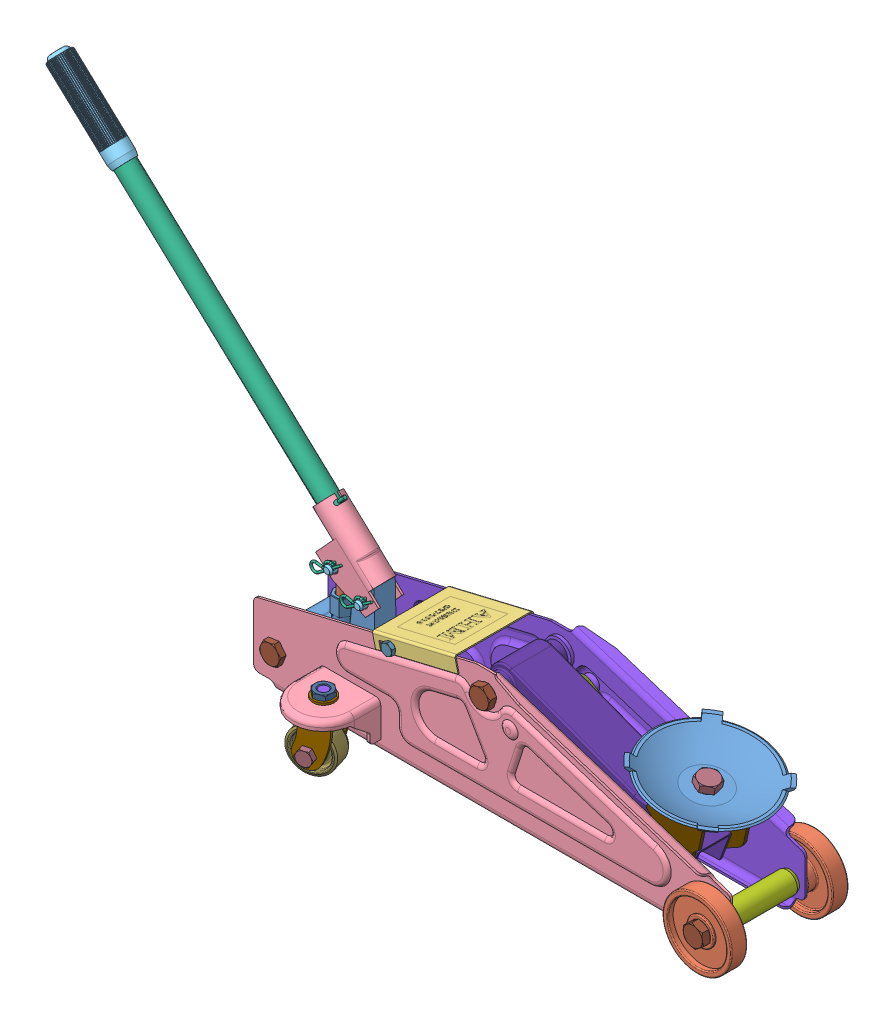
SolidWorks assembly HYDRAULIC FLOOR JACK, configuration Default. Lengths in mm.
Overall size (721.63 435.05 180).
66 component instances, 32 part files, 97 mates.
Components (placement in the parent):
- Part3-1: Part3 [Default] at (-30.7327 -45.0544 -105.304) x (0.999747 0.022492 0) z (0 0 1) size (169.5 91.5 56)
- Part16-1: Part16 [Default] at (-47.0325 12.5554 -112.804) x (-0.022492 0.999747 0) z (-0.262072 -0.005896 0.96503) size (45 10.25 10.25)
- Part14-1: Part14 [Default] at (-47.1112 16.0545 -112.804) x (0 0 1) z (-0.999747 -0.022492 0) size (14 17 19)
- Part6-1: Part6 [Default] at (-25.1366 29.0482 -113.304) x (0.733776 -0.679391 0) z (0 0 1) size (81 40.24 24)
- clevis pin headed_iso-1: clevis pin headed_iso [ISO 2341 - B - 8 x 30 x 2 - St] at (-43.8608 19.1284 -128.304) x (0 0 1) z (-0.796609 -0.604495 0) size (33 14 14)
- clevis pin headed_iso-2: clevis pin headed_iso [ISO 2341 - B - 8 x 30 x 2 - St] at (-15.3389 4.3044 -128.304) x (0 0 1) z (-0.830497 -0.557024 0) size (33 14 14)
- Part17-1: Part17 [Default] at (-4.0659 11.8653 -98.804) x (0.830497 0.557024 0) z (0 0 1) size (33.1 10.2 2)
- Part17-2: Part17 [Default] at (-33.0478 27.3337 -98.804) x (0.796609 0.604495 0) z (0 0 1) size (33.1 10.2 2)
- spring pin slotted_hd_iso2-2: spring pin slotted_hd_iso2 [ISO 8752 - 14 x 65 - St] at (-67.7233 -45.8866 -137.804) x (0 0 1) z (0.610683 -0.791875 0) size (65 14 13.98)
- Part1-1: Part1 [Default] at (361.7767 -71.5391 -140.804) x (-1 0 0) z (0 0 -1) size (450 122.47 64)
- Part15-1: Part15 [Default] at (2.7767 -45.1322 -167.804) x (0.289152 0 -0.957283) z (0.957283 0 0.289152) size (38 61.13 38)
- Part18-1: Part18 [Default] at (-8.112 -40.5391 -173.9429) x (0.278126 -0.941875 0.188462) z (-0.474023 -0.305233 -0.825914) size (6 6 6)
- Part19-1: Part19 [Default] at (2.7767 -40.5391 -167.804) x (-0.010236 0 -0.999948) z (-0.999948 0 0.010236) size (38 2 38)
- Part18-2: Part18 [Default] at (2.6488 -40.5391 -180.3034) x (-0.02415 -0.941875 0.335095) z (0.478251 -0.305233 -0.823473) size (6 6 6)
- Part18-3: Part18 [Default] at (13.5375 -40.5391 -174.1645) x (-0.302276 -0.941875 0.146633) z (0.952275 -0.305233 0.002441) size (6 6 6)
- Part18-4: Part18 [Default] at (13.6654 -40.5391 -161.6652) x (-0.278126 -0.941875 -0.188462) z (0.474023 -0.305233 0.825914) size (6 6 6)
- Part18-5: Part18 [Default] at (2.9046 -40.5391 -155.3047) x (0.02415 -0.941875 -0.335095) z (-0.478251 -0.305233 0.823473) size (6 6 6)
- Part18-6: Part18 [Default] at (-7.9841 -40.5391 -161.4436) x (0.302276 -0.941875 -0.146633) z (-0.952275 -0.305233 -0.002441) size (6 6 6)
- Part10-1: Part10 [Default] at (-2.0097 -76.1322 -169.2498) x (0.846792 0.466391 0.255778) z (0.446468 -0.884579 0.134858) size (40.08 21 40.08)
- hex bolt gradeb_iso-1: hex bolt gradeb_iso [ISO 4015 - M8 x 35 x 22-S] at (3.5709 -76.1322 -187.7254) x (-0.289152 0 0.957283) z (0.028855 0.999546 0.008716) size (40.3 15.01 13)
- hex thin nut gradeb_iso-2: hex thin nut gradeb_iso [ISO - 4036 - M8 - S] at (-7.2145 -76.1322 -152.0187) x (0.374692 -0.920216 0.113178) z (-0.289152 0 0.957283) size (13 15.01 4)
- Part4-1: Part4 [Default] at (-2.2334 -44.4132 -105.304) x (0.999747 0.022492 0) z (-0.022492 0.999747 0) size (133 25 25)
- Part20-1: Part20 [Default] at (210.0163 -29.2774 -137.804) x (0.851833 -0.523814 0) z (0 0 1) size (145 20 3)
- Part5-1: Part5 [Default] at (122.9941 38.2707 -107.804) x (0 0 1) z (0.936412 -0.350903 0) size (58 99.23 200.26)
- Part7-1: Part7 [Default] at (307.743 31.1726 -82.3383) x (0.208686 0.977983 0) z (-0.977983 0.208686 0) size (87.89 54.93 59.06)
- Part9-1: Part9 [Default] at (303.0404 9.1345 -106.804) x (0.702008 -0.149797 -0.696237) z (0.680907 -0.145295 0.717812) size (116.71 17 116.71)
- Part11-1: Part11 [Default] at (349.2767 -59.0438 -143.054) x (-0.815982 0.578077 0) z (-0.578077 -0.815982 0) size (65 19 65)
- spring pin slotted_hd_iso2-3: spring pin slotted_hd_iso2 [ISO 8752 - 18 x 12 - St] at (349.2767 -59.0438 -144.054) x (0 0 -1) z (-0.9622 -0.272344 0) size (12 18 17.97)
- Part8-1: Part8 [Default] at (63.7575 25.6748 -106.804) x (0 0 1) z (0.972806 0.231621 0) size (74 14 80)
- Part2-1: Part2 [Default] at (361.7767 -71.5391 -72.804) x (-1 0 0) z (0 0 -1) size (450 122.47 64)
- Part15-2: Part15 [Default] at (2.7767 -45.1322 -45.804) x (-0.289152 0 -0.957283) z (0.957283 0 -0.289152) size (38 61.13 38)
- Part18-7: Part18 [Default] at (-8.112 -40.5391 -39.6652) x (0.278126 -0.941875 -0.188462) z (0.474023 0.305233 -0.825914) size (6 6 6)
- Part19-2: Part19 [Default] at (2.7767 -40.5391 -45.804) x (0.010236 0 -0.999948) z (-0.999948 0 -0.010236) size (38 2 38)
- Part10-2: Part10 [Default] at (-2.0097 -76.1322 -44.3583) x (0.846792 0.466391 -0.255778) z (-0.446468 0.884579 0.134858) size (40.08 21 40.08)
- hex bolt gradeb_iso-2: hex bolt gradeb_iso [ISO 4015 - M8 x 35 x 22-S] at (3.5709 -76.1322 -25.8827) x (-0.289152 0 -0.957283) z (-0.028855 -0.999546 0.008716) size (40.3 15.01 13)
- hex thin nut gradeb_iso-3: hex thin nut gradeb_iso [ISO - 4036 - M8 - S] at (-6.0578 -76.1322 -57.7602) x (0.374692 -0.920216 -0.113178) z (0.289152 0 0.957283) size (13 15.01 4)
- Part20-2: Part20 [Default] at (210.0163 -29.2774 -78.804) x (0.851833 -0.523814 0) z (0 0 1) size (145 20 3)
- spring pin slotted_hd_iso2-4: spring pin slotted_hd_iso2 [ISO 8752 - 18 x 12 - St] at (349.2767 -59.0438 -57.554) x (0 0 -1) z (-0.9622 -0.272344 0) size (12 18 17.97)
- Part11-2: Part11 [Default] at (349.2767 -59.0438 -70.554) x (-0.815982 0.578077 0) z (0.578077 0.815982 0) size (65 19 65)
- Part12-1: Part12 [Default] at (-251.8735 238.98 -113.304) x (-0.423177 -0.457052 0.78232) z (-0.531501 -0.574048 -0.622877) size (22.2 88 22.2)
- Part21-1: Part21 [Default] at (-33.9419 37.2009 -113.304) x (0.679391 0.733776 0) z (0 0 1) size (26 380 18)
- spring pin slotted_hd_iso-1: spring pin slotted_hd_iso [ISO 8752 - 14 x 65 - St] at (131.7767 18.9609 -139.304) x (0 0 1) z (-0.237226 0.971454 0) size (65 14 13.98)
- hexalobular socket cheese head_iso-1: hexalobular socket cheese head_iso [ISO 14580 - #10 x 16 x 13 - 4.8-S] at (2.7767 -29.1322 -45.804) x (-0.068609 0 -0.997644) z (-0.997644 0 0.068609) size (16 22.9 16)
- plain washer 10673 type snl_iso-1: plain washer 10673 type snl_iso [ISO 10673-11-S] at (2.7767 -33.5391 -45.804) x (0 -1 0) z (-0.63842 0 0.769688) size (2 20 20)
- hex thin nut chamfered gradeab_iso-1: hex thin nut chamfered gradeab_iso [ISO - 4035 - M10 - S] at (2.7767 -28.5391 -45.804) x (0.990758 0 0.135644) z (0 1 0) size (16 18.48 5)
- hex bolt gradeab_iso-1: hex bolt gradeab_iso [ISO 4014 - M12 x 80 x 30-S] at (-67.7233 -45.8866 -65.304) x (0 0 -1) z (-0.143117 0.989706 0) size (87.5 20.78 18)
- hex bolt gradeab_iso-2: hex bolt gradeab_iso [ISO 4014 - M12 x 80 x 30-S] at (131.7767 18.9609 -63.304) x (0 0 -1) z (-0.965945 0.258746 0) size (87.5 20.78 18)
- hex bolt gradeab_iso-3: hex bolt gradeab_iso [ISO 4014 - M12 x 110 x 30-S] at (349.2767 -59.0438 -47.654) x (0 0 -1) z (0.609692 -0.792638 0) size (117.5 20.78 18)
- spring pin slotted_hd_iso-2: spring pin slotted_hd_iso [ISO 8752 - 20 x 65 - St] at (349.2767 -59.0438 -139.304) x (0 0 1) z (-0.928845 -0.370468 0) size (65 20 19.97)
- plain washer clevis pin grade a_iso-1: plain washer clevis pin grade a_iso [ISO 8738 - 12] at (349.2767 -59.0438 -159.054) x (0 0 1) z (-1 0 0) size (3 20 20)
- plain washer clevis pin grade a_iso-2: plain washer clevis pin grade a_iso [ISO 8738 - 12] at (131.7767 18.9609 -142.804) x (0 0 1) z (-1 0 0) size (3 20 20)
- plain washer clevis pin grade a_iso-3: plain washer clevis pin grade a_iso [ISO 8738 - 12] at (-67.7233 -45.8866 -142.804) x (0 0 1) z (-1 0 0) size (3 20 20)
- hex thin nut chamfered gradeab_iso-2: hex thin nut chamfered gradeab_iso [ISO - 4035 - M12 - N] at (349.2767 -59.0438 -168.054) x (0.808569 0.588401 0) z (0 0 -1) size (18 20.78 6)
- hex thin nut chamfered gradeab_iso-3: hex thin nut chamfered gradeab_iso [ISO - 4035 - M12 - N] at (131.7767 18.9609 -151.804) x (0.923728 0.383049 0) z (0 0 -1) size (18 20.78 6)
- hex thin nut chamfered gradeab_iso-4: hex thin nut chamfered gradeab_iso [ISO - 4035 - M12 - N] at (-67.7233 -45.8866 -151.804) x (0.923728 0.383049 0) z (0 0 -1) size (18 20.78 6)
- hexalobular socket cheese head_iso-2: hexalobular socket cheese head_iso [ISO 14580 - #10 x 16 x 13 - 4.8-S] at (2.7767 -29.1322 -167.804) x (-0.068609 0 0.997644) z (0.997644 0 0.068609) size (16 22.9 16)
- plain washer 10673 type snl_iso-2: plain washer 10673 type snl_iso [ISO 10673-11-S] at (2.7767 -33.5391 -167.804) x (0 -1 0) z (0.63842 0 0.769688) size (2 20 20)
- hex thin nut chamfered gradeab_iso-5: hex thin nut chamfered gradeab_iso [ISO - 4035 - M10 - S] at (2.7767 -33.5391 -167.804) x (0.990758 0 -0.135644) z (0 -1 0) size (16 18.48 5)
- clevis pin headed_iso-3: clevis pin headed_iso [ISO 2341 - B - 16 x 50 x 4 - St] at (119.7357 -41.6692 -132.304) x (0 0 1) z (-0.487474 0.873138 0) size (54.5 25 25)
- clevis pin headed_iso-5: clevis pin headed_iso [ISO 2341 - B - 12 x 60 x 3.2 - St] at (292.1959 -41.6871 -75.3383) x (0 0 -1) z (0.694321 -0.719666 0) size (64 20 20)
- hex screw gradeab fine_iso-1: hex screw gradeab fine_iso [ISO 8676 - M12x1.5 x 25-S] at (305.2316 19.4033 -106.804) x (-0.208686 -0.977983 0) z (-0.641055 0.136791 -0.755207) size (32.5 20.78 18)
- hex thin nut chamfered gradeab_iso-6: hex thin nut chamfered gradeab_iso [ISO - 4035 - M12 - S] at (289.2862 2.8668 -107.0926) x (0.965138 -0.205945 0.161538) z (-0.208686 -0.977983 0) size (18 20.78 6)
- hex screw gradeab_iso-1: hex screw gradeab_iso [ISO 4017 - M6 x 12-S] at (41.7767 12.2176 -147.804) x (0 0 1) z (-0.99469 0.102914 0) size (16 11.55 10)
- hex thin nut chamfered gradeab_iso-7: hex thin nut chamfered gradeab_iso [ISO - 4035 - M6 - S] at (41.7767 12.2176 -137.604) x (0.611351 0.79136 0) z (0 0 1) size (10 11.55 3.2)
- hex screw gradeab_iso-2: hex screw gradeab_iso [ISO 4017 - M6 x 12-S] at (41.7767 12.2176 -65.804) x (0 0 -1) z (0.99469 -0.102914 0) size (16 11.55 10)
- hex thin nut chamfered gradeab_iso-8: hex thin nut chamfered gradeab_iso [ISO - 4035 - M6 - S] at (41.7767 12.2176 -72.804) x (0.611351 0.79136 0) z (0 0 1) size (10 11.55 3.2)
Mates (geometry in assembly coordinates):
- Concentric3: concentric aligned: cylinder of Part3-1 through (-45.6614 -48.391 -112.804) axis (-0.022492 0.999747 0) radius 5; cylinder of Part16-1 through (-47.0325 12.5554 -112.804) axis (-0.022492 0.999747 0) radius 4.25
- Concentric4: concentric anti-aligned: cylinder of Part16-1 through (-47.0325 12.5554 -112.804) axis (-0.022492 0.999747 0) radius 3.25; cylinder of Part14-1 through (-47.3024 24.5533 -112.804) axis (0.022492 -0.999747 0) radius 3.375
- Width1: width anti-aligned: plane of Part14-1 through (-54.4519 8.8876 -105.804) normal (-0.022492 0.999747 0); plane of Part16-1 through (-54.4182 7.388 -105.804) normal (0.022492 -0.999747 0); plane of Part14-1 through (-46.9538 9.0563 -112.804) normal (0.022492 -0.999747 0); plane of Part16-1 through (-46.9201 7.5566 -112.804) normal (-0.022492 0.999747 0)
- Concentric5: concentric anti-aligned: cylinder of Part6-1 through (-15.3389 4.3044 -101.304) axis (0 0 -1) radius 4.5; cylinder of Part3-1 through (-15.3389 4.3044 -133.304) axis (0 0 1) radius 4.25
- Width2: width anti-aligned: plane of Part3-1 through (-30.7327 -45.0544 -123.304) normal (0 0 -1); plane of Part6-1 through (-30.7327 -45.0544 -103.304) normal (0 0 1); plane of Part3-1 through (-25.1366 29.0482 -123.304) normal (0 0 1); plane of Part6-1 through (-25.1366 29.0482 -103.304) normal (0 0 -1)
- Parallel1: parallel aligned: plane of Part14-1 through (-41.7138 20.6771 -119.804) normal (0 0 -1); plane of Part6-1 through (-25.1366 29.0482 -125.304) normal (0 0 -1)
- Concentric6: concentric anti-aligned: cylinder of Part6-1 through (-43.8608 19.1284 -125.304) axis (0 0 1) radius 5; cylinder of clevis pin headed_iso-1 through (-43.8608 19.1284 -128.304) axis (0 0 -1) radius 7
- Coincident1: coincident anti-aligned: plane of Part6-1 through (-25.1366 29.0482 -125.304) normal (0 0 -1); plane of clevis pin headed_iso-1 through (-48.0923 24.7046 -125.304) normal (0 0 1)
- Concentric7: concentric anti-aligned: cylinder of Part6-1 through (-15.3389 4.3044 -125.304) axis (0 0 1) radius 4.5; cylinder of clevis pin headed_iso-2 through (-15.3389 4.3044 -128.304) axis (0 0 -1) radius 7
- Coincident2: coincident anti-aligned: plane of Part6-1 through (-25.1366 29.0482 -125.304) normal (0 0 -1); plane of clevis pin headed_iso-2 through (-19.2381 10.1178 -125.304) normal (0 0 1)
- Tangent2: tangent anti-aligned: plane of Part14-1 through (-52.7673 22.929 -105.804) normal (0.022492 -0.999747 0); cylinder of clevis pin headed_iso-1 through (-43.8608 19.1284 -128.304) axis (0 0 -1) radius 4
- LimitDistance1: limit distance = 15.9618 mm anti-aligned: plane of Part14-1 through (-54.4182 7.388 -105.804) normal (0.022492 -0.999747 0); plane of Part3-1 through (-31.5649 -8.0637 -105.304) normal (-0.022492 0.999747 0)
- Concentric8: concentric aligned: cylinder of clevis pin headed_iso-1 through (-40.6744 21.5464 -98.804) axis (-0.796609 -0.604495 0) radius 1; cylinder of Part17-2 through (-33.0478 27.3337 -98.804) axis (-0.796609 -0.604495 0) radius 1
- Concentric9: concentric aligned: cylinder of clevis pin headed_iso-2 through (-12.0169 6.5325 -98.804) axis (-0.830497 -0.557024 0) radius 1; cylinder of Part17-1 through (-4.0659 11.8653 -98.804) axis (-0.830497 -0.557024 0) radius 1
- Tangent3: tangent anti-aligned: cylinder of clevis pin headed_iso-1 through (-43.8608 19.1284 -128.304) axis (0 0 -1) radius 4; cylinder of Part17-2 through (-48.9777 18.617 -98.804) axis (0.135845 0.99073 0) radius 1
- Parallel2: parallel aligned: plane of Part6-1 through (-25.1366 29.0482 -101.304) normal (0 0 1); plane of Part17-2 through (-33.0478 27.3337 -98.804) normal (0 0 1)
- Parallel4: parallel aligned: plane of Part6-1 through (-25.1366 29.0482 -101.304) normal (0 0 1); plane of Part17-1 through (-4.0659 11.8653 -98.804) normal (0 0 1)
- Tangent5: tangent anti-aligned: cylinder of clevis pin headed_iso-2 through (-15.3389 4.3044 -128.304) axis (0 0 -1) radius 4; cylinder of Part17-1 through (-20.4769 4.0922 -98.804) axis (0.193374 0.981125 0) radius 1
- Concentric12: concentric aligned: cylinder of Part3-1 through (-67.7233 -45.8866 -133.304) axis (0 0 1) radius 7.5; cone of spring pin slotted_hd_iso-2 through (-67.7233 -45.8866 -72.804) axis (0 0 1)
- Width3: width anti-aligned: plane of spring pin slotted_hd_iso-2 through (-72.6725 -49.7033 -137.804) normal (0 0 -1); plane of Part3-1 through (-70.8908 -48.3293 -72.804) normal (0 0 1); plane of spring pin slotted_hd_iso-2 through (-67.7233 -45.8866 -77.304) normal (0 0 1); plane of Part3-1 through (-67.7233 -45.8866 -133.304) normal (0 0 -1)
- Concentric13: concentric aligned: cylinder of spring pin slotted_hd_iso-2 through (-67.7233 -45.8866 -147.329) axis (0 0 -1) radius 4; cylinder of Part1-1 through (-67.7233 -45.8866 -137.804) axis (0 0 -1) radius 7.5
- Coincident8: coincident anti-aligned: plane of spring pin slotted_hd_iso-2 through (-72.6725 -49.7033 -137.804) normal (0 0 -1); plane of Part1-1 through (-67.7233 -45.8866 -137.804) normal (0 0 1)
- Concentric14: concentric: sphere of Part18-1; sphere of Part19-1
- Concentric15: concentric aligned: circle of Part1-1; circle of Part19-1
- Concentric16: concentric anti-aligned: cylinder of Part1-1 through (2.7767 42.9337 -167.804) axis (0 -1 0) radius 6.5; cylinder of Part15-1 through (2.7767 -26.9992 -167.804) axis (0 1 0) radius 7
- Tangent17: tangent anti-aligned: torus of Part1-1; sphere of Part18-3
- Concentric17: concentric anti-aligned: cylinder of Part15-1 through (-6.0578 -76.1322 -155.8478) axis (0.289152 0 -0.957283) radius 5; cylinder of Part10-1 through (-5.9086 -76.1322 -156.3419) axis (-0.289152 0 0.957283) radius 5
- Width4: width anti-aligned: plane of Part10-1 through (-3.2076 -78.4641 -180.5802) normal (0.289152 0 -0.957283); plane of Part15-1 through (-9.2798 -78.4641 -160.4772) normal (-0.289152 0 0.957283); plane of Part10-1 through (17.7399 -59.5549 -174.7752) normal (-0.289152 0 0.957283); plane of Part15-1 through (11.3786 -59.5549 -153.7149) normal (0.289152 0 -0.957283)
- Concentric18: concentric anti-aligned: cylinder of Part15-1 through (2.0384 -76.1322 -182.6518) axis (-0.289152 0 0.957283) radius 5; cylinder of hex bolt gradeb_iso-1 through (3.5709 -76.1322 -187.7254) axis (0.289152 0 -0.957283) radius 4
- Coincident10: coincident anti-aligned: plane of Part15-1 through (18.6074 -59.5549 -177.647) normal (0.289152 0 -0.957283); plane of hex bolt gradeb_iso-1 through (9.2201 -76.3584 -180.4825) normal (-0.289152 0 0.957283)
- Concentric19: concentric anti-aligned: cylinder of Part15-1 through (-6.0578 -76.1322 -155.8478) axis (0.289152 0 -0.957283) radius 12; cylinder of hex thin nut gradeb_iso-2 through (0.0252 -76.1322 -175.9867) axis (-0.289152 0 0.957283) radius 4
- Coincident11: coincident anti-aligned: plane of Part15-1 through (10.5111 -59.5549 -150.8431) normal (-0.289152 0 0.957283); plane of hex thin nut gradeb_iso-2 through (0.5538 -73.1944 -153.8507) normal (0.289152 0 -0.957283)
- Concentric21: concentric aligned: cylinder of Part3-1 through (-81.2209 -46.1902 -105.304) axis (0.999747 0.022492 0) radius 7.5; cylinder of Part4-1 through (130.733 -41.4218 -105.304) axis (0.999747 0.022492 0) radius 7.5
- Concentric22: concentric aligned: cylinder of Part1-1 through (156.7767 3.4609 -133.804) axis (0 0 -1) radius 4.5; cylinder of Part20-1 through (156.7767 3.4609 -134.804) axis (0 0 -1) radius 5.75
- Coincident13: coincident anti-aligned: plane of Part1-1 through (131.7767 18.9609 -137.804) normal (0 0 1); plane of Part20-1 through (156.7767 3.4609 -137.804) normal (0 0 -1)
- Concentric26: concentric aligned: cylinder of Part1-1 through (131.7767 18.9609 -137.804) axis (0 0 -1) radius 7.5; cylinder of Part5-1 through (131.7767 18.9609 -78.804) axis (0 0 -1) radius 10.5
- Distance3: distance = 1 mm anti-aligned: plane of Part1-1 through (131.7767 18.9609 -137.804) normal (0 0 1); plane of Part5-1 through (131.7767 18.9609 -136.804) normal (0 0 -1)
- Concentric28: concentric anti-aligned: cylinder of Part4-1 through (119.7357 -41.6692 -92.804) axis (0 0 -1) radius 8; cylinder of Part5-1 through (119.7357 -41.6692 -127.814) axis (0 0 1) radius 8
- Parallel11: parallel anti-aligned: plane of Part1-1 through (351.7767 -79.5391 -135.804) normal (0 -1 0)
- Concentric29: concentric anti-aligned: cylinder of Part5-1 through (292.1959 -41.6871 -127.814) axis (0 0 1) radius 6.5; cylinder of Part7-1 through (292.1959 -41.6871 -79.3383) axis (0 0 -1) radius 6.25
- Concentric30: concentric anti-aligned: cylinder of Part20-1 through (263.2558 -62.0157 -134.804) axis (0 0 -1) radius 5.75; cylinder of Part7-1 through (263.2558 -62.0157 -134.2697) axis (0 0 1) radius 5.5
- Tangent18: tangent anti-aligned: torus of Part15-1; sphere of Part18-4
- Linear/Linear Coupler3: linear coupler = 1 : 4 mm: cylinder of Part16-1 through (-47.0325 12.5554 -112.804) axis (-0.022492 0.999747 0) radius 4.25; cylinder of Part4-1 through (130.733 -41.4218 -105.304) axis (0.999747 0.022492 0) radius 7.5
- Concentric32: concentric aligned: cylinder of Part7-1 through (284.6998 -76.8167 -106.804) axis (0.208686 0.977983 0) radius 6.5; cylinder of Part9-1 through (303.0404 9.1345 -106.804) axis (0.208686 0.977983 0) radius 6.5
- Coincident18: coincident anti-aligned: plane of Part7-1 through (279.5095 14.1556 -6.3836) normal (0.208686 0.977983 0); plane of Part9-1 through (303.0404 9.1345 -106.804) normal (-0.208686 -0.977983 0)
- Concentric33: concentric aligned: cylinder of Part1-1 through (349.2767 -59.0438 -132.804) axis (0 0 -1) radius 5.5; cylinder of Part11-1 through (349.2767 -59.0438 -171.148) axis (0 0 -1) radius 9
- Distance4: distance = 0.25 mm anti-aligned: plane of Part1-1 through (361.7767 -71.5391 -142.804) normal (0 0 -1); plane of Part11-1 through (359.8845 -66.5588 -143.054) normal (0 0 1)
- Concentric34: concentric aligned: cylinder of Part11-1 through (349.2767 -59.0438 -171.148) axis (0 0 -1) radius 9; cone of spring pin slotted_hd_iso-3 through (349.2767 -59.0438 -156.054) axis (0 0 -1)
- Concentric36: concentric anti-aligned: cylinder of Part5-1 through (131.7767 18.9609 -78.804) axis (0 0 -1) radius 8; cylinder of Part2-1 through (131.7767 18.9609 -80.804) axis (0 0 1) radius 6.5
- Concentric37: concentric anti-aligned: cylinder of Part1-1 through (41.7767 12.2176 -132.804) axis (0 0 -1) radius 3.5; cylinder of Part8-1 through (41.7767 12.2176 -143.804) axis (0 0 1) radius 3
- Coincident19: coincident anti-aligned: plane of Part1-1 through (361.7767 -71.5391 -142.804) normal (0 0 -1); plane of Part8-1 through (63.7575 25.6748 -142.804) normal (0 0 1)
- Parallel12: parallel anti-aligned: plane of Part1-1 through (-88.2233 -11.5391 -142.804) normal (-0.231621 0.972806 0); plane of Part8-1 through (27.8563 3.7635 -143.804) normal (0.231621 -0.972806 0)
- Concentric38: concentric aligned: cylinder of Part8-1 through (41.7767 12.2176 -143.804) axis (0 0 1) radius 3; cylinder of Part2-1 through (41.7767 12.2176 -80.804) axis (0 0 1) radius 3.5
- Coincident21: coincident anti-aligned: plane of Part8-1 through (63.7575 25.6748 -70.804) normal (0 0 -1); plane of Part2-1 through (361.7767 -71.5391 -70.804) normal (0 0 1)
- Coincident22: coincident anti-aligned: plane of Part12-1 through (-312.7769 295.3694 -113.304) normal (0.733776 -0.679391 0); plane of Part21-1 through (-312.7769 295.3694 -113.304) normal (-0.733776 0.679391 0)
- Concentric39: concentric aligned: cylinder of Part12-1 through (-314.2445 296.7282 -113.304) axis (0.733776 -0.679391 0) radius 9; cylinder of Part21-1 through (-312.7769 295.3694 -113.304) axis (0.733776 -0.679391 0) radius 9
- Concentric40: concentric aligned: cylinder of Part6-1 through (-60.3578 61.6589 -113.304) axis (0.733776 -0.679391 0) radius 10; cylinder of Part21-1 through (-312.7769 295.3694 -113.304) axis (0.733776 -0.679391 0) radius 9
- Parallel13: parallel anti-aligned: cylinder of Part6-1 through (-42.3674 72.2581 -117.304) axis (-0.679391 -0.733776 0) radius 2; face of Part21-1
- Distance5: distance = 28 mm aligned: plane of Part21-1 through (-33.9419 37.2009 -113.304) normal (-0.733776 0.679391 0); plane of Part6-1 through (-40.8998 70.8993 -113.304) normal (-0.733776 0.679391 0)
- Concentric41: concentric aligned: cylinder of Part2-1 through (131.7767 18.9609 -75.804) axis (0 0 1) radius 7.5; cone of spring pin slotted_hd_iso-1 through (131.7767 18.9609 -74.304) axis (0 0 1)
- Width6: width aligned: plane of spring pin slotted_hd_iso-1 through (135.6625 19.9098 -74.304) normal (0 0 1); plane of Part2-1 through (137.8483 20.4436 -139.304) normal (0 0 -1); plane of spring pin slotted_hd_iso-1 through (361.7767 -71.5391 -70.804) normal (0 0 1); plane of Part1-1 through (361.7767 -71.5391 -142.804) normal (0 0 -1)
- Concentric42: concentric anti-aligned: cylinder of Part19-2 through (2.7767 -41.5391 -45.804) axis (0 1 0) radius 7; cone of hexalobular socket cheese head_iso-1 through (2.7767 -45.1322 -45.804) axis (0 -1 0)
- Coincident24: coincident anti-aligned: plane of Part2-1 through (31.7767 -35.5391 -16.804) normal (0 1 0); plane of plain washer 10673 type snl_iso-1 through (2.7767 -35.5391 -45.804) normal (0 -1 0)
- Concentric43: concentric anti-aligned: circle of hexalobular socket cheese head_iso-1; circle of plain washer 10673 type snl_iso-1
- Concentric44: concentric anti-aligned: cone of hexalobular socket cheese head_iso-1 through (2.7767 -29.6009 -45.804) axis (0 -1 0); cylinder of hex thin nut chamfered gradeab_iso-1 through (2.7767 -53.5766 -45.804) axis (0 1 0) radius 5
- Coincident26: coincident anti-aligned: plane of plain washer 10673 type snl_iso-1 through (2.7767 -33.5391 -45.804) normal (0 1 0); plane of hex thin nut chamfered gradeab_iso-1 through (4.0297 -33.5391 -54.9563) normal (0 -1 0)
- Coincident27: coincident anti-aligned: plane of Part15-2 through (4.8008 -45.1322 -39.1031) normal (0 -1 0); plane of hexalobular socket cheese head_iso-1 through (2.4337 -45.1322 -50.7923) normal (0 1 0)
- Concentric45: concentric anti-aligned: cylinder of Part1-1 through (-67.7233 -45.8866 -137.804) axis (0 0 -1) radius 7.5; cylinder of hex bolt gradeab_iso-1 through (-67.7233 -45.8866 -65.304) axis (0 0 1) radius 9
- Coincident28: coincident anti-aligned: plane of spring pin slotted_hd_iso2-2 through (-70.8908 -48.3293 -72.804) normal (0 0 1); plane of hex bolt gradeab_iso-1 through (-78.0086 -47.3739 -72.804) normal (0 0 -1)
- Concentric46: concentric aligned: cylinder of Part2-1 through (131.7767 18.9609 -80.804) axis (0 0 1) radius 6.5; cylinder of hex bolt gradeab_iso-2 through (131.7767 18.9609 -63.304) axis (0 0 1) radius 9
- Coincident29: coincident anti-aligned: plane of Part2-1 through (361.7767 -71.5391 -70.804) normal (0 0 1); plane of hex bolt gradeab_iso-2 through (129.0877 8.9225 -70.804) normal (0 0 -1)
- Concentric47: concentric aligned: cylinder of Part2-1 through (349.2767 -59.0438 -80.804) axis (0 0 1) radius 5.5; cylinder of hex bolt gradeab_iso-3 through (349.2767 -59.0438 -47.654) axis (0 0 1) radius 9
- Coincident31: coincident anti-aligned: plane of Part11-2 through (356.6205 -64.2465 -54.554) normal (0 0 1); plane of hex bolt gradeab_iso-3 through (356.4104 -53.5565 -54.554) normal (0 0 -1)
- Width71: width anti-aligned: plane of spring pin slotted_hd_iso-2 through (345.9425 -50.6842 -139.304) normal (0 0 -1); plane of spring pin slotted_hd_iso-2 through (347.0539 -53.4707 -74.304) normal (0 0 1); plane of Part1-1 through (361.7767 -71.5391 -140.804) normal (0 0 1); plane of Part2-1 through (361.7767 -71.5391 -72.804) normal (0 0 -1)
- Concentric50: concentric aligned: cone of hex bolt gradeab_iso-3 through (349.2767 -59.0438 -165.154) axis (0 0 -1); cylinder of plain washer clevis pin grade a_iso-1 through (349.2767 -59.0438 -193.979) axis (0 0 -1) radius 6
- Concentric51: concentric aligned: cone of hex bolt gradeab_iso-2 through (131.7767 18.9609 -150.804) axis (0 0 -1); cylinder of plain washer clevis pin grade a_iso-2 through (131.7767 18.9609 -177.729) axis (0 0 -1) radius 6
- Concentric52: concentric aligned: cone of hex bolt gradeab_iso-1 through (-67.7233 -45.8866 -152.804) axis (0 0 -1); cylinder of plain washer clevis pin grade a_iso-3 through (-67.7233 -45.8866 -177.729) axis (0 0 -1) radius 6
- Coincident371: coincident anti-aligned: plane of Part11-1 through (356.6205 -64.2465 -159.054) normal (0 0 -1); plane of plain washer clevis pin grade a_iso-1 through (349.2767 -53.0438 -159.054) normal (0 0 1)
- Coincident381: coincident anti-aligned: plane of Part1-1 through (361.7767 -71.5391 -142.804) normal (0 0 -1); plane of plain washer clevis pin grade a_iso-2 through (131.7767 24.9609 -142.804) normal (0 0 1)
- Coincident391: coincident anti-aligned: plane of Part1-1 through (361.7767 -71.5391 -142.804) normal (0 0 -1); plane of plain washer clevis pin grade a_iso-3 through (-67.7233 -39.8866 -142.804) normal (0 0 1)
- Concentric53: concentric aligned: cone of hex bolt gradeab_iso-3 through (349.2767 -59.0438 -165.154) axis (0 0 -1); cylinder of hex thin nut chamfered gradeab_iso-2 through (349.2767 -59.0438 -143.0165) axis (0 0 -1) radius 6
- Concentric54: concentric aligned: cone of hex bolt gradeab_iso-2 through (131.7767 18.9609 -150.804) axis (0 0 -1); cylinder of hex thin nut chamfered gradeab_iso-3 through (131.7767 18.9609 -126.7665) axis (0 0 -1) radius 6
- Concentric55: concentric aligned: cone of hex bolt gradeab_iso-1 through (-67.7233 -45.8866 -152.804) axis (0 0 -1); cylinder of hex thin nut chamfered gradeab_iso-4 through (-67.7233 -45.8866 -126.7665) axis (0 0 -1) radius 6
- Coincident441: coincident anti-aligned: plane of plain washer clevis pin grade a_iso-3 through (-67.7233 -35.8866 -145.804) normal (0 0 -1); plane of hex thin nut chamfered gradeab_iso-4 through (-63.7425 -55.4862 -145.804) normal (0 0 1)
- Coincident451: coincident anti-aligned: plane of plain washer clevis pin grade a_iso-2 through (131.7767 28.9609 -145.804) normal (0 0 -1); plane of hex thin nut chamfered gradeab_iso-3 through (135.7575 9.3613 -145.804) normal (0 0 1)
- Concentric581: concentric aligned: cylinder of Part4-1 through (119.7357 -41.6692 -92.804) axis (0 0 -1) radius 8; cylinder of clevis pin headed_iso-3 through (119.7357 -41.6692 -132.304) axis (0 0 -1) radius 8
- Coincident471: coincident anti-aligned: plane of Part5-1 through (122.9941 38.2707 -127.804) normal (0 0 -1); plane of clevis pin headed_iso-3 through (130.65 -35.5758 -127.804) normal (0 0 1)
- Concentric60: concentric anti-aligned: cylinder of Part7-1 through (292.1959 -41.6871 -79.3383) axis (0 0 -1) radius 6.25; cylinder of clevis pin headed_iso-5 through (292.1959 -41.6871 -75.3383) axis (0 0 1) radius 10
- Coincident49: coincident anti-aligned: plane of Part7-1 through (263.2558 -62.0157 -79.3383) normal (0 0 1); plane of clevis pin headed_iso-5 through (299.3925 -34.7439 -79.3383) normal (0 0 -1)
- Width101: width anti-aligned: plane of Part7-1 through (263.2558 -62.0157 -79.3383) normal (0 0 1); plane of Part7-1 through (305.1684 134.4032 -134.2697) normal (0 0 -1); plane of Part20-2 through (156.7767 3.4609 -78.804) normal (0 0 -1); plane of Part20-1 through (156.7767 3.4609 -134.804) normal (0 0 1)
- Concentric69: concentric aligned: cylinder of Part9-1 through (303.0404 9.1345 -106.804) axis (0.208686 0.977983 0) radius 6.5; cylinder of hex screw gradeab fine_iso-1 through (305.2316 19.4033 -106.804) axis (0.208686 0.977983 0) radius 9
- Coincident53: coincident anti-aligned: plane of Part9-1 through (303.6664 12.0684 -106.804) normal (0.208686 0.977983 0); plane of hex screw gradeab fine_iso-1 through (295.9909 13.7063 -99.992) normal (-0.208686 -0.977983 0)
- Coincident551: coincident anti-aligned: plane of Part7-1 through (278.8835 11.2216 -6.3836) normal (-0.208686 -0.977983 0); plane of hex thin nut chamfered gradeab_iso-6 through (288.8966 9.085 -96.8368) normal (0.208686 0.977983 0)
- Concentric70: concentric anti-aligned: cylinder of Part8-1 through (41.7767 12.2176 -143.804) axis (0 0 1) radius 3; cylinder of hex screw gradeab_iso-1 through (41.7767 12.2176 -147.804) axis (0 0 -1) radius 5
- Coincident571: coincident anti-aligned: plane of Part8-1 through (63.7575 25.6748 -143.804) normal (0 0 -1); plane of hex screw gradeab_iso-1 through (42.3709 17.9605 -143.804) normal (0 0 1)
- Concentric721: concentric anti-aligned: circle of hex screw gradeab_iso-1; circle of hex thin nut chamfered gradeab_iso-7
- Coincident581: coincident anti-aligned: plane of Part1-1 through (361.7767 -71.5391 -140.804) normal (0 0 1); plane of hex thin nut chamfered gradeab_iso-7 through (37.2078 15.7473 -140.804) normal (0 0 -1)
